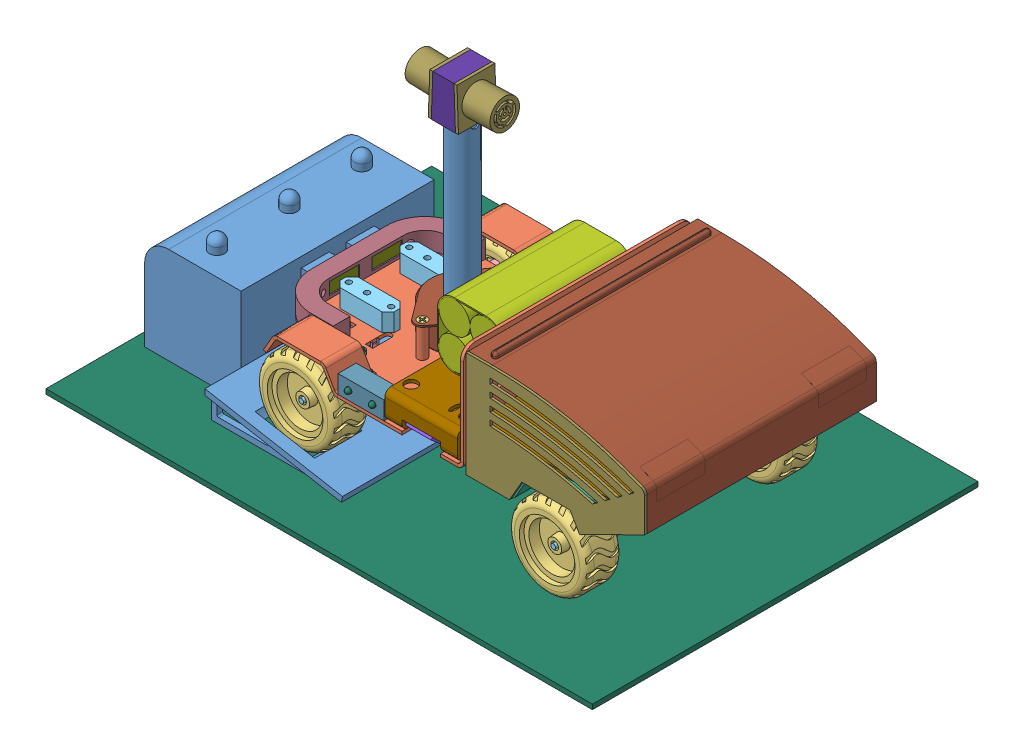
SolidWorks assembly Charging Test Assembly, configuration Default. Lengths in mm.
Overall size (287.48 162.48 202.9).
72 component instances, 34 part files, 13 mates.
Components (placement in the parent):
- Station Shell-1: Station Shell [Default] at (-113.9035 -9.7247 66.6257) size (123.18 58.42 139.7)
- REAR, TOP LEVEL-1: REAR, TOP LEVEL [Default] at (-11.5087 -1.8645 107.5685) x (0 0 1) z (-1 0 0) size (124.43 158.23 120.66)
  - PLATE, REAR-1: PLATE, REAR [Default] at (-42.1312 28.0774 12.7174) size (120.65 55.63 120.66)
  - WHEEL ASSEMBLY-1: WHEEL ASSEMBLY [Default-_flexible1] at (7.6153 26.9792 58.7651) x (0 0 1) z (1 0 0) size (42.46 78.6 70.03) (flexible)
    - Pololu 49x19 Wheel-1: Pololu 49x19 Wheel [Default] at (-19.8703 11.8393 2.4418) size (42.46 42.56 19)
    - Pololu Extended Micro Metal Bracket-1: Pololu Extended Micro Metal Bracket [Default] at (-19.8703 6.8393 -18.4366) size (26.6 22.49 26.04)
    - Pololu 298-1 Motor-1: Pololu 298-1 Motor [Default] at (-19.8703 11.8393 -25.1366) x (0 0 -1) z (0 1 0) size (35.87 12 10)
  - WHEEL ASSEMBLY-2: WHEEL ASSEMBLY [Default-_flexible2] at (-91.8778 26.9792 19.0244) x (0 0 -1) z (-1 0 0) size (42.46 78.6 70.03) (flexible)
    - Pololu 49x19 Wheel-1: Pololu 49x19 Wheel [Default] at (-19.8703 11.8393 2.4418) size (42.46 42.56 19)
    - Pololu Extended Micro Metal Bracket-1: Pololu Extended Micro Metal Bracket [Default] at (-19.8703 6.8393 -18.4366) size (26.6 22.49 26.04)
    - Pololu 298-1 Motor-1: Pololu 298-1 Motor [Default] at (-19.8703 11.8393 -25.1366) x (0 0 -1) z (0 1 0) size (35.87 12 10)
  - Socket Head Cap Screw_AI-1: Socket Head Cap Screw_AI [HX-SHCS 0.086-56x0.4375x0.4375-N] at (-77.6912 31.9128 47.8948) x (0 -1 0) z (-0.381305 0 -0.924449) size (13.3 3.56 3.56)
  - Socket Head Cap Screw_AI-2: Socket Head Cap Screw_AI [HX-SHCS 0.086-56x0.4375x0.4375-N] at (-77.6912 31.9128 29.8948) x (0 -1 0) z (0 0 1) size (13.3 3.56 3.56)
  - Socket Head Cap Screw_AI-3: Socket Head Cap Screw_AI [HX-SHCS 0.086-56x0.4375x0.4375-N] at (-6.5712 31.9128 29.8948) x (0 -1 0) z (0 0 1) size (13.3 3.56 3.56)
  - Socket Head Cap Screw_AI-4: Socket Head Cap Screw_AI [HX-SHCS 0.086-56x0.4375x0.4375-N] at (-6.5712 31.9128 47.8948) x (0 -1 0) z (0 0 1) size (13.3 3.56 3.56)
  - 4000mAh 7.4V Battery Pack-1: 4000mAh 7.4V Battery Pack [Default] at (-42.1312 61.2244 -25.7652) x (0 0 -1) z (1 0 0) size (34.29 34.29 68.58)
  - SENSOR, GP2Y0D810-1: SENSOR, GP2Y0D810 [Default] at (9.9271 36.6454 -23.9555) x (0 0 -1) z (0.766044 0.642788 0) size (28.32 10.54 8.89)
  - SENSOR, GP2Y0D810-2: SENSOR, GP2Y0D810 [Default] at (-94.1896 36.6454 -23.9555) x (0 0 -1) z (0.766044 -0.642788 0) size (28.32 10.54 8.89)
  - Battery Support-1: Battery Support [Default] at (-42.1312 29.7284 -26.0192) size (120.65 27.05 38.1)
  - Mounting Block-1: Mounting Block [Default] at (-42.1312 36.0784 -35.6712) x (-1 0 0) z (0 0 -1) size (25.4 12.7 25.4)
  - PF35T-48-1: PF35T-48 [Default] at (-42.1312 31.7284 12.5888) size (50 29.2 35)
  - MaxSonar EZ1-1: MaxSonar EZ1 [Default] at (-42.1312 140.4691 6.6293) x (-1 0 0) z (0 0.034899 -0.999391) size (19.94 22.1 16.38)
  - MaxSonar EZ1-2: MaxSonar EZ1 [Default] at (-42.1312 140.4691 18.5483) x (1 0 0) z (0 0.034899 0.999391) size (19.94 22.1 16.38)
  - BUMPER, REAR-1: BUMPER, REAR [Default] at (-42.1312 29.7284 53.2288) x (-1 0 0) z (0 0 -1) size (80.01 9.53 31.76)
  - PLATE, REAR COVER-1: PLATE, REAR COVER [Default] at (-42.1312 39.2534 72.2788) size (120.65 0.81 81.14) (hidden)
  - MOUNTING BLOCK, COLOR SENSOR-1: MOUNTING BLOCK, COLOR SENSOR [Default] at (-97.6937 29.7284 5.6038) size (9.53 9.53 24.13)
  - MOUNTING BLOCK, COLOR SENSOR-2: MOUNTING BLOCK, COLOR SENSOR [Default] at (13.4313 29.7284 5.6038) size (9.53 9.53 24.13)
  - SENSOR, COLOR LED-1: SENSOR, COLOR LED [Default] at (-24.0807 23.782 31.9371) x (0 0 -1) z (-0.409692 -0.912224 0) size (5.83 3.66 3.66)
  - SENSOR, COLOR LED-2: SENSOR, COLOR LED [Default] at (-67.3741 22.996 31.9371) x (0 0 -1) z (-0.202984 -0.979182 0) size (5.83 3.66 3.66)
  - COPPER CONTACT-1: COPPER CONTACT [Default] at (-53.2437 34.4909 64.0238) size (15.88 6.35 4.45)
  - COPPER CONTACT-2: COPPER CONTACT [Default] at (-31.0187 34.4909 64.0238) size (15.88 6.35 4.45)
  - MOUNTING BLOCK, SONAR-1: MOUNTING BLOCK, SONAR [Default] at (-42.1312 140.3989 12.5888) x (-1 0 0) z (0 0 -1) size (19.94 22.23 12.7)
  - SHAFT, SONAR MOUNT-1: SHAFT, SONAR MOUNT [Default] at (-42.1312 52.5784 12.5888) x (-0.538443 0 0.842662) z (-0.842662 0 -0.538443) size (4.76 89.41 4.76)
  - SHAFT, SONAR SUPPORT-1: SHAFT, SONAR SUPPORT [Default] at (-42.1312 46.7284 12.5888) x (0.999987 0 0.005105) z (-0.005105 0 0.999987) size (14.22 82.87 14.22)
  - SHAFT, STEPPER SUPPORT-1: SHAFT, STEPPER SUPPORT [Default] at (-63.1312 29.6724 12.5888) size (4.76 16.26 4.76)
  - SHAFT, STEPPER SUPPORT-2: SHAFT, STEPPER SUPPORT [Default] at (-21.1312 29.6724 12.5888) x (0.987866 0 -0.155311) z (0.155311 0 0.987866) size (4.76 16.26 4.76)
  - Flat Head 100 Screw_AI-2: Flat Head 100 Screw_AI [CR-FHM1 0.112-40x0.25x0.25-N] at (-63.1312 46.7284 12.5888) x (0 -1 0) z (0 0 1) size (6.35 4.85 4.85)
  - Flat Head 100 Screw_AI-3: Flat Head 100 Screw_AI [CR-FHM1 0.112-40x0.25x0.25-N] at (-21.1312 46.7284 12.5888) x (0 -1 0) z (0 0 1) size (6.35 4.85 4.85)
  - CONNECTOR, MOLEX 6 PIN-1: CONNECTOR, MOLEX 6 PIN [Default] at (-80.2263 37.7912 12.5433) size (10.34 13.8 9.75)
  - SENSOR, COLOR LED-3: SENSOR, COLOR LED [Default] at (-64.0196 42.7147 3.5765) x (1 0 0) z (0 0.700538 -0.713616) size (5.83 3.66 3.66)
  - SENSOR, COLOR LED-4: SENSOR, COLOR LED [Default] at (-64.0196 42.7147 -9.1235) x (1 0 0) z (0 0.700538 -0.713616) size (5.83 3.66 3.66)
  - SENSOR, COLOR LED-5: SENSOR, COLOR LED [Default] at (-20.2429 42.7147 20.3311) x (-1 0 0) z (0 0.700538 0.713616) size (5.83 3.66 3.66)
  - SENSOR, COLOR LED-6: SENSOR, COLOR LED [Default] at (-20.2429 42.7147 7.6311) x (-1 0 0) z (0 0.700538 0.713616) size (5.83 3.66 3.66)
  - MOUNTING BLOCK, REAR-1: MOUNTING BLOCK, REAR [Default] at (-58.0062 34.4909 31.0038) size (9.53 9.53 28.57)
  - MOUNTING BLOCK, REAR-2: MOUNTING BLOCK, REAR [Default] at (-26.2562 34.4909 31.0038) size (9.53 9.53 28.57)
- FRONT, TOP LEVEL-1: FRONT, TOP LEVEL [Default] at (64.5283 -20.2944 141.9007) x (0 0 1) z (-1 0 0) size (123.38 92.39 123.83)
  - PLATE, FRONT-1: PLATE, FRONT [Default] at (-76.4634 46.5072 -32.0242) size (120.65 12.1 60.8)
  - WHEEL ASSEMBLY-1: WHEEL ASSEMBLY [Default-_flexible3] at (-26.7168 45.4091 2.1802) x (0 0 1) z (1 0 0) size (42.46 78.6 70.03) (flexible)
    - Pololu 49x19 Wheel-1: Pololu 49x19 Wheel [Default] at (-19.8703 11.8393 2.4418) size (42.46 42.56 19)
    - Pololu Extended Micro Metal Bracket-1: Pololu Extended Micro Metal Bracket [Default] at (-19.8703 6.8393 -18.4366) size (26.6 22.49 26.04)
    - Pololu 298-1 Motor-1: Pololu 298-1 Motor [Default] at (-19.8703 11.8393 -25.1366) x (0 0 -1) z (0 1 0) size (35.87 12 10)
  - WHEEL ASSEMBLY-2: WHEEL ASSEMBLY [Default-_flexible4] at (-126.21 45.4091 -37.5605) x (0 0 -1) z (-1 0 0) size (42.46 78.6 70.03) (flexible)
    - Pololu 49x19 Wheel-1: Pololu 49x19 Wheel [Default] at (-19.8703 11.8393 2.4418) size (42.46 42.56 19)
    - Pololu Extended Micro Metal Bracket-1: Pololu Extended Micro Metal Bracket [Default] at (-19.8703 6.8393 -18.4366) size (26.6 22.49 26.04)
    - Pololu 298-1 Motor-1: Pololu 298-1 Motor [Default] at (-19.8703 11.8393 -25.1366) x (0 0 -1) z (0 1 0) size (35.87 12 10)
  - Socket Head Cap Screw_AI-1: Socket Head Cap Screw_AI [HX-SHCS 0.086-56x0.4375x0.4375-N] at (-112.0234 50.3426 -8.6902) x (0 -1 0) z (0.989468 0 0.144748) size (13.3 3.56 3.56)
  - Socket Head Cap Screw_AI-3: Socket Head Cap Screw_AI [HX-SHCS 0.086-56x0.4375x0.4375-N] at (-40.9034 50.3426 -8.6902) x (0 -1 0) z (0.700957 0 0.713204) size (13.3 3.56 3.56)
  - SENSOR, GP2Y0D810-2: SENSOR, GP2Y0D810 [Default] at (-76.7491 52.0249 -21.9932) x (1 0 0) z (0 -0.642788 0.766044) size (28.32 10.54 8.89)
  - BUMPER, FRONT-1: BUMPER, FRONT [Default] at (-76.4634 36.9822 -30.9902) x (-1 0 0) z (0 0 -1) size (69.85 9.53 6.35)
  - Mounting Block-1: Mounting Block [Default] at (-76.4634 54.5082 12.4258) size (25.4 12.7 25.4)
  - Socket Head Shoulder Screw2_AI-1: Socket Head Shoulder Screw2_AI [SHSSCREW 0.25x1.5-N] at (-76.4634 54.5082 2.5706) x (0 0 1) z (-0.728467 -0.685081 0) size (52.4 9.53 9.53)
  - Socket Head Cap Screw_AI-5: Socket Head Cap Screw_AI [HX-SHCS 0.086-56x0.4375x0.4375-N] at (-40.9034 51.2773 -26.6902) x (0 -1 0) z (-0.957829 0 -0.287339) size (13.3 3.56 3.56)
  - Socket Head Cap Screw_AI-6: Socket Head Cap Screw_AI [HX-SHCS 0.086-56x0.4375x0.4375-N] at (-112.0234 51.2773 -26.6902) x (0 -1 0) z (-0.957829 0 -0.287339) size (13.3 3.56 3.56)
  - PCB, MAIN-1: PCB, MAIN [Default] at (-76.4634 67.2082 -19.3242) size (114.3 6.68 88.9)
  - PLATE, FRONT BUMPER-1: PLATE, FRONT BUMPER [Default] at (-76.4634 48.9202 -22.7941) size (120.65 17.91 44.79)
  - COVER, FRONT-1: COVER, FRONT [Default] at (-76.4634 65.9382 25.1258) size (120.65 38.73 93.98)
  - PLATE, FRONT SIDE-1: PLATE, FRONT SIDE [Default] at (-16.1384 46.5072 25.1258) x (0 0 -1) z (1 0 0) size (93.98 55.63 1.27)
  - SW3dPS-USB_mini_B-1: SW3dPS-USB_mini_B [По умолчанию] at (-54.9865 68.8084 -56.2867) x (-1 0 0) z (0 0 -1) size (10.7 4.95 9.2)
- purple LED-1: purple LED [Default] at (-113.9035 4.2262 116.465) x (0 -1 0) z (0 0 1) size (5.83 3.66 3.66)
- purple LED-2: purple LED [Default] at (-113.9035 4.2262 78.365) x (0 -1 0) z (0 0 1) size (5.83 3.66 3.66)
- purple LED-3: purple LED [Default] at (-113.9035 4.2262 40.265) x (0 -1 0) z (0 0 1) size (5.83 3.66 3.66)
- Ground-1: Ground [Default] at (-30.2243 -12.2647 76.1359) size (287.48 2.54 202.9)
Mates (geometry in assembly coordinates):
- Parallel1: parallel anti-aligned: plane of REAR, TOP LEVEL-1/PLATE, REAR-1 through (-30.4475 26.2128 25.4323) normal (0 -1 0); plane of Station Shell-1 through (-84.7125 -6.7275 133.1229) normal (0 1 0)
- Distance1: distance = 3 mm anti-aligned: plane of REAR, TOP LEVEL-1/WHEEL ASSEMBLY-1/Pololu 49x19 Wheel-1 through (-50.4035 13.2753 127.1257) normal (0 0 1); plane of Station Shell-1 through (-50.4035 13.2753 130.1257) normal (0 0 -1)
- Concentric1: concentric anti-aligned: cylinder of Station Shell-1; cylinder of REAR, TOP LEVEL-1/WHEEL ASSEMBLY-1/Pololu 49x19 Wheel-1
- Concentric2: concentric anti-aligned: cylinder of REAR, TOP LEVEL-1/Mounting Block-1; cylinder of FRONT, TOP LEVEL-1/Socket Head Shoulder Screw2_AI-1
- Distance2: distance = 2.54 mm anti-aligned: plane of REAR, TOP LEVEL-1/Mounting Block-1 through (36.8625 40.5638 52.7373) normal (1 0 0); plane of FRONT, TOP LEVEL-1/Mounting Block-1 through (39.4025 40.5638 78.1373) normal (-1 0 0)
- Parallel2: parallel aligned: plane of REAR, TOP LEVEL-1/PLATE, REAR-1 through (-30.4475 26.2128 25.4323) normal (0 -1 0); plane of FRONT, TOP LEVEL-1/PLATE, FRONT-1 through (62.2625 26.2128 25.4323) normal (0 -1 0)
- Coincident4: coincident aligned: plane of purple LED-1 through (-115.7542 38.7258 106.5765) normal (0 -1 0); plane of purple LED-2 through (-115.7542 38.7258 68.4765) normal (0 -1 0)
- Coincident5: coincident aligned: plane of purple LED-2 through (-115.7542 38.7258 68.4765) normal (0 -1 0); plane of purple LED-3 through (-115.7542 38.7258 30.3765) normal (0 -1 0)
- Coincident6: coincident anti-aligned: plane of Station Shell-1 through (-126.6035 39.4878 117.4257) normal (0 -1 0); plane of purple LED-2 through (-115.7542 39.4878 64.775) normal (0 1 0)
- Concentric3: concentric anti-aligned: cylinder of Station Shell-1; cylinder of purple LED-3
- Concentric4: concentric anti-aligned: cylinder of Station Shell-1; cylinder of purple LED-2
- Concentric5: concentric anti-aligned: cylinder of Station Shell-1; cylinder of purple LED-1
- Coincident7: coincident anti-aligned: plane of Ground-1 through (-146.1826 -9.7247 -40.4925) normal (0 1 0); plane of Station Shell-1 through (-139.3035 -9.7247 117.4257) normal (0 -1 0)
